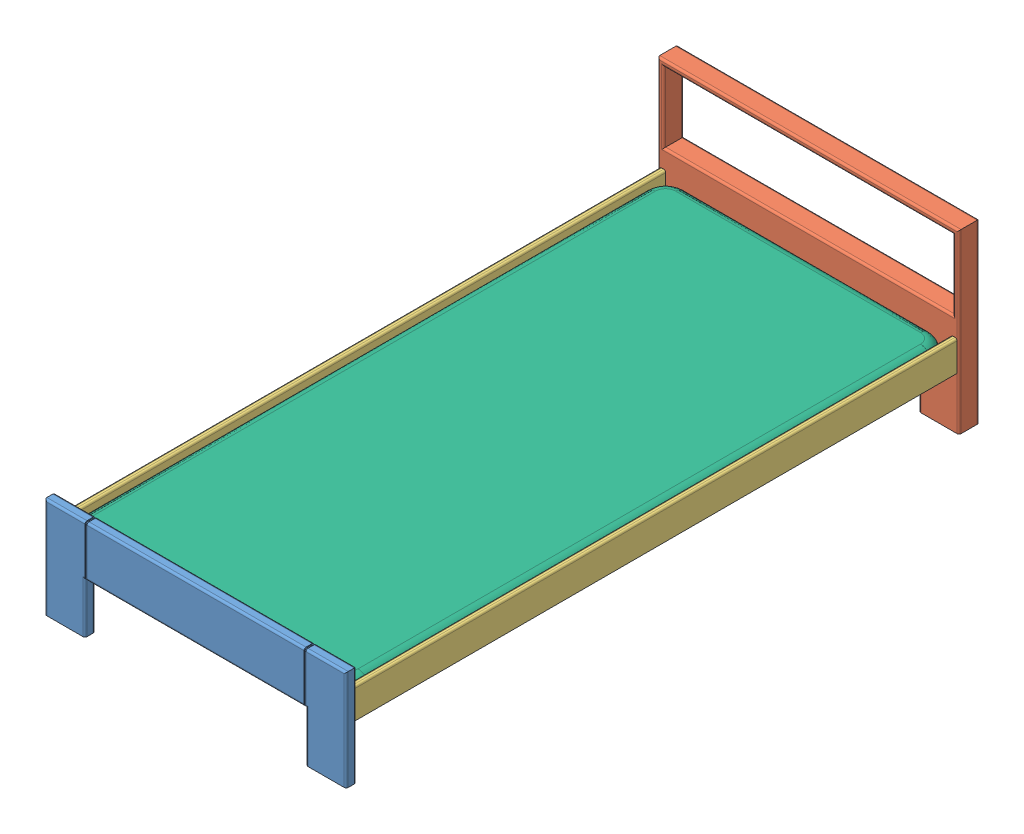
SolidWorks assembly Assem1, configuration Default. Lengths in mm.
Overall size (1500 880 3150).
7 component instances, 6 part files, 18 mates.
Components (placement in the parent):
- Back-1: Back [Default] at (644.6122 1209.3026 961.7565) size (1500 500 50)
- Front-1: Front [Default] at (764.9483 1209.3026 -2138.2435) size (1500 880 100)
- Sides-2: Sides [Default] at (-95.3878 1044.3026 961.7565) x (-1 0 0) z (0 0 -1) size (60 150 3000)
- Sides-3: Sides [Default] at (1384.6122 1044.3026 -2038.2435) size (60 150 3000)
- Support-1: Support [Default] at (1354.6122 999.3026 -2038.2435) x (1 0 0) z (0 1 0) size (1420 3000 4)
- Sentex-1: Sentex [Default] at (1345.7204 1103.3026 974.8967) x (1 0 0) z (0 -1 0) size (1400 2980 100)
- Cover-1: Cover [Default] at (1334.6122 1105.3026 961.7565) x (1 0 0) z (0 -1 0) size (1419 2999 100)
Mates (geometry in assembly coordinates):
- Coincident1: coincident anti-aligned: plane of Back-1 through (644.6122 1209.3026 961.7565) normal (0 0 -1); plane of Sides-1 through (1384.6122 1044.3026 961.7565) normal (0 0 1)
- Coincident6: coincident anti-aligned: line of Back-1 through (1204.6122 969.3026 961.7565) axis (-1 0 0); line of Sides-1 through (1324.6122 969.3026 961.7565) axis (1 0 0)
- Coincident7: coincident anti-aligned: line of Back-1 through (1384.6122 1199.3026 961.7565) axis (0 -1 0); line of Sides-1 through (1384.6122 969.3026 961.7565) axis (0 1 0)
- Coincident8: coincident aligned: line of Back-1 through (1204.6122 969.3026 961.7565) axis (-1 0 0); line of Sides-2 through (-35.3878 969.3026 961.7565) axis (-1 0 0)
- Coincident9: coincident aligned: line of Back-1 through (-95.3878 709.3026 961.7565) axis (0 1 0); line of Sides-2 through (-95.3878 969.3026 961.7565) axis (0 1 0)
- Coincident10: coincident anti-aligned: line of Front-1 through (-95.3878 1579.3026 -2038.2435) axis (0 -1 0); line of Sides-2 through (-95.3878 969.3026 -2038.2435) axis (0 1 0)
- Coincident11: coincident anti-aligned: line of Front-1 through (84.6122 969.3026 -2038.2435) axis (1 0 0); line of Sides-2 through (-35.3878 969.3026 -2038.2435) axis (-1 0 0)
- Coincident12: coincident aligned: line of Front-1 through (1384.6122 709.3026 -2038.2435) axis (0 1 0); line of Sides-3 through (1384.6122 969.3026 -2038.2435) axis (0 1 0)
- Coincident13: coincident aligned: line of Front-1 through (84.6122 969.3026 -2038.2435) axis (1 0 0); line of Sides-3 through (1324.6122 969.3026 -2038.2435) axis (1 0 0)
- Coincident17: coincident anti-aligned: plane of Back-1 through (644.6122 1209.3026 961.7565) normal (0 0 -1); plane of Support-1 through (-65.3878 1003.3026 961.7565) normal (0 0 1)
- Coincident18: coincident anti-aligned: plane of Sides-2 through (-65.3878 1119.3026 -2038.2435) normal (1 0 0); plane of Support-1 through (-65.3878 1003.3026 -2038.2435) normal (-1 0 0)
- Coincident19: coincident anti-aligned: plane of Sides-2 through (-65.3878 999.3026 -2038.2435) normal (0 1 0); plane of Support-1 through (1354.6122 999.3026 -2038.2435) normal (0 -1 0)
- Coincident20: coincident anti-aligned: plane of Support-1 through (1354.6122 1003.3026 -2038.2435) normal (0 1 0); plane of Sentex-1 through (45.7204 1003.3026 -3033.8848) normal (0 -1 0)
- Coincident21: coincident anti-aligned: plane of Sentex-1 through (45.7204 1103.3026 -3033.8848) normal (0 1 0); plane of Cover-1 through (34.6122 1103.3026 -3047.025) normal (0 -1 0)
- Lock1: lock: unknown of Sentex-1; unknown of Cover-1
- Coincident23: coincident anti-aligned: plane of Support-1 through (1354.6122 1003.3026 -2038.2435) normal (0 1 0); plane of Sentex-1 through (45.7204 1003.3026 -3033.8848) normal (0 -1 0)
- Coincident24: coincident anti-aligned: plane of Sides-2 through (-65.3878 1119.3026 -2038.2435) normal (1 0 0); plane of Cover-1 through (-65.3878 905.3026 -248.025) normal (-1 0 0)
- Coincident25: coincident anti-aligned: plane of Back-1 through (644.6122 1209.3026 961.7565) normal (0 0 -1); plane of Cover-1 through (34.6122 905.3026 961.7565) normal (0 0 1)
